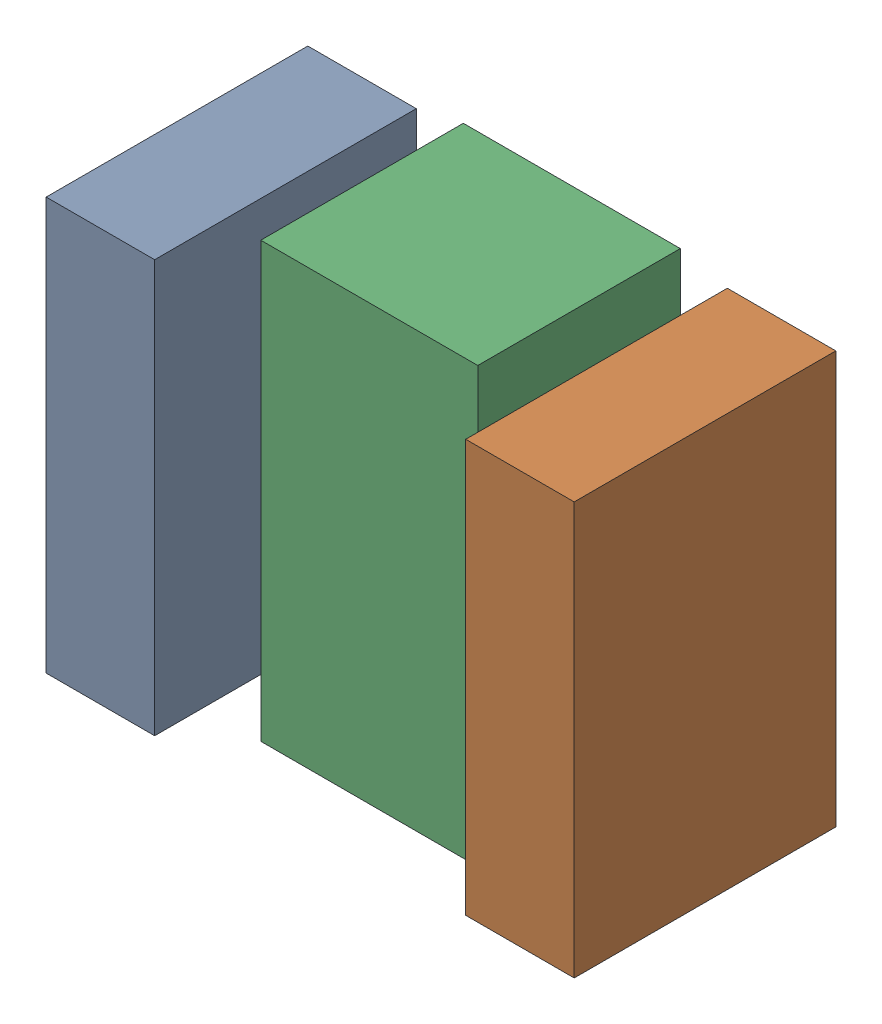
SolidWorks assembly C7_Motor_10Kanaloa_v2.0.0_Motor, configuration Default. Lengths in mm.
Overall size (3.65 3 1.81).
6 component instances, 2 part files, 0 mates.
Components (placement in the parent):
- 334788400-1: 334788400 [Default] at (102.198 167.386 0) size (0.75 2.85 1.81)
  - Extruded_5-1: Extruded_5 [Default] at origin size (0.75 2.85 1.81)
- 334788400-2: 334788400 [Default] at (105.098 167.386 0) size (0.75 2.85 1.81)
  - Extruded_5-1: Extruded_5 [Default] at origin size (0.75 2.85 1.81)
- 334788656-1: 334788656 [Default] at (103.648 167.386 0) size (1.5 3 1.4)
  - Extruded_1-1: Extruded_1 [Default] at origin size (1.5 3 1.4)
